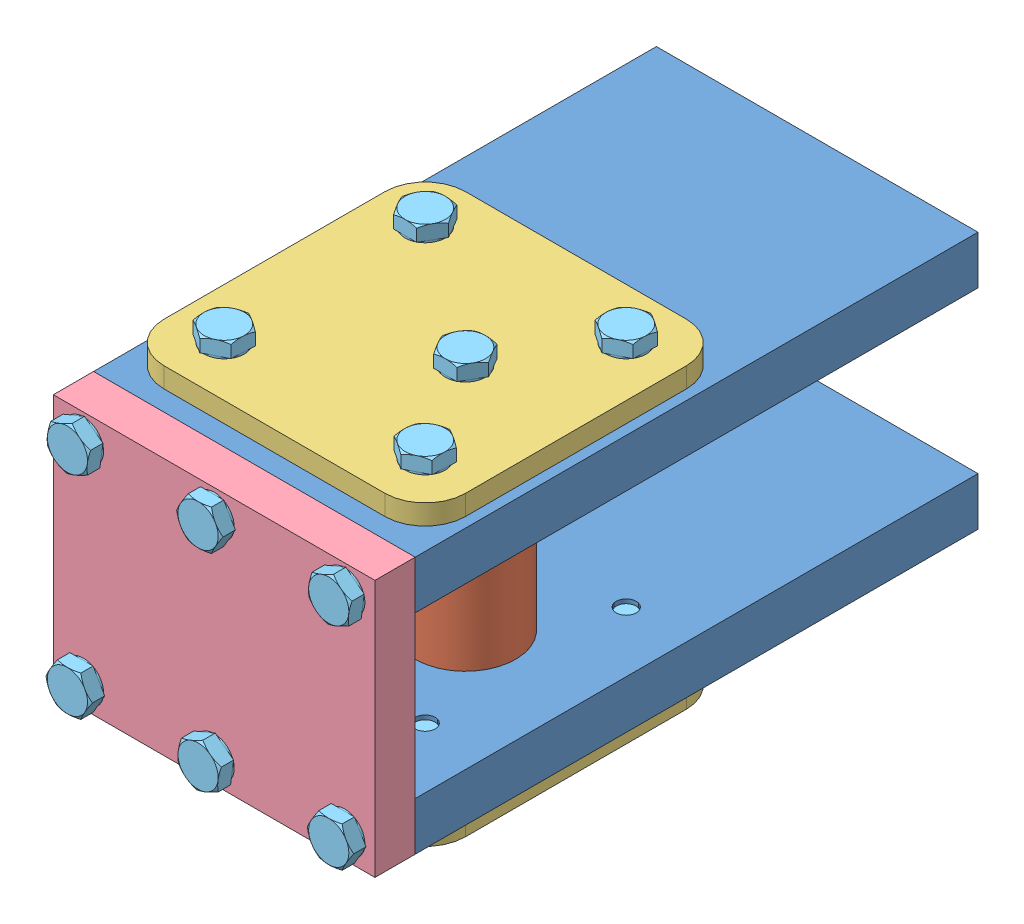
SolidWorks assembly 010300_cylinder_mount, configuration Default. Lengths in mm.
Overall size (80 82 154).
22 component instances, 5 part files, 49 mates.
Components (placement in the parent):
- 010301_cylinder_mount_front-1: 010301_cylinder_mount_front [Default] at (0 -26 0) size (80 12 140)
- 010301_cylinder_mount_front-2: 010301_cylinder_mount_front [Default] at (0 26 0) size (80 12 140)
- 010302_cylinder_mount_pin-1: 010302_cylinder_mount_pin [Default] at (10 0 -42.5) x (0.998607 0 0.052773) z (0 -1 0) size (25 25 64)
- 010303_cylinder_mount_pincover-1: 010303_cylinder_mount_pincover [Default] at (0 32 -42.5) x (1 0 0) z (0 1 0) size (75 75 5)
- 010303_cylinder_mount_pincover-2: 010303_cylinder_mount_pincover [Default] at (0 -32 -42.5) x (1 0 0) z (0 -1 0) size (75 75 5)
- 010304_cylinder_mount_bottom-1: 010304_cylinder_mount_bottom [Default] at (-40 0 0) size (80 64 10)
- hex screw gradeab_iso-1: hex screw gradeab_iso [ISO 4017 - M6 x 16-N] at (-25 41 -67.5) x (0 -1 0) z (0 0 -1) size (20 11.55 10)
- hex screw gradeab_iso-2: hex screw gradeab_iso [ISO 4017 - M6 x 16-N] at (25 41 -67.5) x (0 -1 0) z (-0.546944 0 0.837169) size (20 11.55 10)
- hex screw gradeab_iso-3: hex screw gradeab_iso [ISO 4017 - M6 x 16-N] at (10 41 -42.5) x (0 -1 0) z (0 0 -1) size (20 11.55 10)
- hex screw gradeab_iso-4: hex screw gradeab_iso [ISO 4017 - M6 x 16-N] at (-25 41 -17.5) x (0 -1 0) z (-0.546944 0 0.837169) size (20 11.55 10)
- hex screw gradeab_iso-5: hex screw gradeab_iso [ISO 4017 - M6 x 16-N] at (25 41 -17.5) x (0 -1 0) z (-0.546944 0 0.837169) size (20 11.55 10)
- hex screw gradeab_iso-6: hex screw gradeab_iso [ISO 4017 - M6 x 16-N] at (-25 -41 -67.5) x (0 1 0) z (-0.546944 0 -0.837169) size (20 11.55 10)
- hex screw gradeab_iso-7: hex screw gradeab_iso [ISO 4017 - M6 x 16-N] at (25 -41 -67.5) x (0 1 0) z (-0.546944 0 -0.837169) size (20 11.55 10)
- hex screw gradeab_iso-8: hex screw gradeab_iso [ISO 4017 - M6 x 16-N] at (10 -41 -42.5) x (0 1 0) z (-0.546944 0 -0.837169) size (20 11.55 10)
- hex screw gradeab_iso-9: hex screw gradeab_iso [ISO 4017 - M6 x 16-N] at (-25 -41 -17.5) x (0 1 0) z (0 0 1) size (20 11.55 10)
- hex screw gradeab_iso-10: hex screw gradeab_iso [ISO 4017 - M6 x 16-N] at (25 -41 -17.5) x (0 1 0) z (0 0 1) size (20 11.55 10)
- hex screw gradeab_iso-11: hex screw gradeab_iso [ISO 4017 - M6 x 16-N] at (-32.5 26 14) x (0 0 -1) z (0.383049 -0.923728 0) size (20 11.55 10)
- hex screw gradeab_iso-12: hex screw gradeab_iso [ISO 4017 - M6 x 16-N] at (0 26 14) x (0 0 -1) z (0 1 0) size (20 11.55 10)
- hex screw gradeab_iso-13: hex screw gradeab_iso [ISO 4017 - M6 x 16-N] at (0 -26 14) x (0 0 -1) z (0.383049 -0.923728 0) size (20 11.55 10)
- hex screw gradeab_iso-14: hex screw gradeab_iso [ISO 4017 - M6 x 16-N] at (32.5 -26 14) x (0 0 -1) z (0 1 0) size (20 11.55 10)
- hex screw gradeab_iso-15: hex screw gradeab_iso [ISO 4017 - M6 x 16-N] at (-32.5 -26 14) x (0 0 -1) z (0 1 0) size (20 11.55 10)
- hex screw gradeab_iso-16: hex screw gradeab_iso [ISO 4017 - M6 x 16-N] at (32.5 26 14) x (0 0 -1) z (0.383049 -0.923728 0) size (20 11.55 10)
Mates (geometry in assembly coordinates):
- Coincident1: coincident aligned: plane of 010301_cylinder_mount_front-1 through (0 -26 0) normal (0 0 1)
- Coincident3: coincident aligned: plane of 010301_cylinder_mount_front-1 through (0 -26 0) normal (1 0 0)
- Concentric1: concentric anti-aligned: cylinder of 010301_cylinder_mount_front-2 through (10 32 -42.5) axis (0 -1 0) radius 12.5; cylinder of 010302_cylinder_mount_pin-1 through (10 -32 -42.5) axis (0 1 0) radius 12.5
- Coincident13: coincident aligned: plane of 010301_cylinder_mount_front-2 through (0 32 0) normal (0 1 0); plane of 010302_cylinder_mount_pin-1 through (10 32 -42.5) normal (0 1 0)
- Concentric2: concentric anti-aligned: cylinder of 010301_cylinder_mount_front-1 through (10 -20 -42.5) axis (0 -1 0) radius 12.5; cylinder of 010302_cylinder_mount_pin-1 through (10 -32 -42.5) axis (0 1 0) radius 12.5
- Coincident17: coincident aligned: plane of 010301_cylinder_mount_front-1 through (0 -32 0) normal (0 -1 0); plane of 010302_cylinder_mount_pin-1 through (10 -32 -42.5) normal (0 -1 0)
- Coincident18: coincident anti-aligned: plane of 010302_cylinder_mount_pin-1 through (10 0 -42.5) normal (0 -1 0)
- Coincident20: coincident aligned: plane of 010301_cylinder_mount_front-1 through (-40 -20 -140) normal (-1 0 0); plane of 010301_cylinder_mount_front-2 through (-40 32 -140) normal (-1 0 0)
- Coincident23: coincident anti-aligned: plane of 010301_cylinder_mount_front-2 through (0 32 0) normal (0 1 0); plane of 010303_cylinder_mount_pincover-1 through (0 32 -42.5) normal (0 -1 0)
- Concentric5: concentric aligned: cylinder of 010301_cylinder_mount_front-2 through (25 32 -67.5) axis (0 1 0) radius 2.5; circle of Cylinderfixture_pincover-1
- Concentric6: concentric aligned: cylinder of 010301_cylinder_mount_front-2 through (25 32 -17.5) axis (0 1 0) radius 2.5; cylinder of 010303_cylinder_mount_pincover-1 through (25 37 -17.5) axis (0 1 0) radius 3.5
- Coincident24: coincident anti-aligned: plane of 010301_cylinder_mount_front-1 through (0 -32 0) normal (0 -1 0); plane of 010303_cylinder_mount_pincover-2 through (0 -32 -42.5) normal (0 1 0)
- Concentric7: concentric anti-aligned: cylinder of 010301_cylinder_mount_front-1 through (25 -20 -67.5) axis (0 1 0) radius 2.5; cylinder of 010303_cylinder_mount_pincover-2 through (25 -37 -67.5) axis (0 -1 0) radius 3.5
- Concentric8: concentric anti-aligned: cylinder of 010301_cylinder_mount_front-1 through (25 -20 -17.5) axis (0 1 0) radius 2.5; cylinder of 010303_cylinder_mount_pincover-2 through (25 -37 -17.5) axis (0 -1 0) radius 3.5
- Concentric9: concentric aligned: cylinder of 010303_cylinder_mount_pincover-1 through (-25 37 -67.5) axis (0 1 0) radius 3.5; cylinder of hex screw gradeab_iso-1 through (-25 41 -67.5) axis (0 1 0) radius 3
- Concentric10: concentric aligned: cylinder of 010303_cylinder_mount_pincover-1 through (25 37 -67.5) axis (0 1 0) radius 3.5; cylinder of hex screw gradeab_iso-2 through (25 41 -67.5) axis (0 1 0) radius 3
- Concentric11: concentric aligned: cylinder of 010303_cylinder_mount_pincover-1 through (10 37 -42.5) axis (0 1 0) radius 3.5; cylinder of hex screw gradeab_iso-3 through (10 41 -42.5) axis (0 1 0) radius 3
- Concentric12: concentric aligned: cylinder of 010303_cylinder_mount_pincover-1 through (-25 37 -17.5) axis (0 1 0) radius 3.5; cylinder of hex screw gradeab_iso-4 through (-25 41 -17.5) axis (0 1 0) radius 3
- Concentric13: concentric aligned: cylinder of 010303_cylinder_mount_pincover-1 through (25 37 -17.5) axis (0 1 0) radius 3.5; cylinder of hex screw gradeab_iso-5 through (25 41 -17.5) axis (0 1 0) radius 3
- Coincident25: coincident anti-aligned: plane of 010303_cylinder_mount_pincover-1 through (0 37 -42.5) normal (0 1 0); plane of hex screw gradeab_iso-3 through (4.2265 37 -42.5) normal (0 -1 0)
- Coincident26: coincident anti-aligned: plane of 010303_cylinder_mount_pincover-1 through (0 37 -42.5) normal (0 1 0); plane of hex screw gradeab_iso-1 through (-30.7735 37 -67.5) normal (0 -1 0)
- Coincident27: coincident anti-aligned: plane of 010303_cylinder_mount_pincover-1 through (0 37 -42.5) normal (0 1 0); plane of hex screw gradeab_iso-2 through (29.8334 37 -64.3422) normal (0 -1 0)
- Coincident28: coincident anti-aligned: plane of 010303_cylinder_mount_pincover-1 through (0 37 -42.5) normal (0 1 0); plane of hex screw gradeab_iso-4 through (-20.1666 37 -14.3422) normal (0 -1 0)
- Coincident29: coincident anti-aligned: plane of 010303_cylinder_mount_pincover-1 through (0 37 -42.5) normal (0 1 0); plane of hex screw gradeab_iso-5 through (29.8334 37 -14.3422) normal (0 -1 0)
- Concentric14: concentric aligned: cylinder of 010303_cylinder_mount_pincover-2 through (25 -37 -67.5) axis (0 -1 0) radius 3.5; cylinder of hex screw gradeab_iso-7 through (25 -41 -67.5) axis (0 -1 0) radius 3
- Concentric15: concentric aligned: cylinder of 010303_cylinder_mount_pincover-2 through (-25 -37 -67.5) axis (0 -1 0) radius 3.5; cylinder of hex screw gradeab_iso-6 through (-25 -41 -67.5) axis (0 -1 0) radius 3
- Concentric16: concentric aligned: cylinder of 010303_cylinder_mount_pincover-2 through (10 -37 -42.5) axis (0 -1 0) radius 3.5; cylinder of hex screw gradeab_iso-8 through (10 -41 -42.5) axis (0 -1 0) radius 3
- Concentric17: concentric aligned: cylinder of 010303_cylinder_mount_pincover-2 through (-25 -37 -17.5) axis (0 -1 0) radius 3.5; cylinder of hex screw gradeab_iso-9 through (-25 -41 -17.5) axis (0 -1 0) radius 3
- Concentric18: concentric aligned: cylinder of 010303_cylinder_mount_pincover-2 through (25 -37 -17.5) axis (0 -1 0) radius 3.5; cylinder of hex screw gradeab_iso-10 through (25 -41 -17.5) axis (0 -1 0) radius 3
- Coincident31: coincident anti-aligned: plane of 010303_cylinder_mount_pincover-2 through (0 -37 -42.5) normal (0 -1 0); plane of hex screw gradeab_iso-6 through (-20.1666 -37 -70.6578) normal (0 1 0)
- Coincident32: coincident anti-aligned: plane of 010303_cylinder_mount_pincover-2 through (0 -37 -42.5) normal (0 -1 0); plane of hex screw gradeab_iso-7 through (29.8334 -37 -70.6578) normal (0 1 0)
- Coincident33: coincident anti-aligned: plane of 010303_cylinder_mount_pincover-2 through (0 -37 -42.5) normal (0 -1 0); plane of hex screw gradeab_iso-8 through (14.8334 -37 -45.6578) normal (0 1 0)
- Coincident34: coincident anti-aligned: plane of 010303_cylinder_mount_pincover-2 through (0 -37 -42.5) normal (0 -1 0); plane of hex screw gradeab_iso-9 through (-30.7735 -37 -17.5) normal (0 1 0)
- Coincident35: coincident anti-aligned: plane of 010303_cylinder_mount_pincover-2 through (0 -37 -42.5) normal (0 -1 0); plane of hex screw gradeab_iso-10 through (19.2265 -37 -17.5) normal (0 1 0)
- Coincident36: coincident anti-aligned: plane of 010301_cylinder_mount_front-2 through (-40 32 0) normal (0 0 1); plane of 010304_cylinder_mount_bottom-1 through (-40 0 0) normal (0 0 -1)
- Coincident37: coincident aligned: plane of 010301_cylinder_mount_front-2 through (0 32 0) normal (0 1 0); plane of 010304_cylinder_mount_bottom-1 through (-40 32 10) normal (0 1 0)
- Coincident38: coincident aligned: plane of 010301_cylinder_mount_front-2 through (40 32 -140) normal (1 0 0); plane of 010304_cylinder_mount_bottom-1 through (40 32 10) normal (1 0 0)
- Concentric19: concentric aligned: cylinder of 010304_cylinder_mount_bottom-1 through (-32.5 26 10) axis (0 0 1) radius 3.5; cylinder of hex screw gradeab_iso-11 through (-32.5 26 14) axis (0 0 1) radius 3
- Concentric20: concentric aligned: cylinder of 010304_cylinder_mount_bottom-1 through (0 26 10) axis (0 0 1) radius 3.5; cylinder of hex screw gradeab_iso-12 through (0 26 14) axis (0 0 1) radius 3
- Concentric21: concentric aligned: cylinder of 010304_cylinder_mount_bottom-1 through (32.5 26 10) axis (0 0 1) radius 3.5; cylinder of hex screw gradeab_iso-16 through (32.5 26 14) axis (0 0 1) radius 3
- Concentric22: concentric aligned: cylinder of 010304_cylinder_mount_bottom-1 through (-32.5 -26 10) axis (0 0 1) radius 3.5; cylinder of hex screw gradeab_iso-15 through (-32.5 -26 14) axis (0 0 1) radius 3
- Concentric23: concentric aligned: cylinder of 010304_cylinder_mount_bottom-1 through (0 -26 10) axis (0 0 1) radius 3.5; cylinder of hex screw gradeab_iso-13 through (0 -26 14) axis (0 0 1) radius 3
- Concentric24: concentric aligned: cylinder of 010304_cylinder_mount_bottom-1 through (32.5 -26 10) axis (0 0 1) radius 3.5; cylinder of hex screw gradeab_iso-14 through (32.5 -26 14) axis (0 0 1) radius 3
- Coincident39: coincident anti-aligned: plane of 010304_cylinder_mount_bottom-1 through (-40 0 10) normal (0 0 1); plane of hex screw gradeab_iso-15 through (-38.2735 -26 10) normal (0 0 -1)
- Coincident40: coincident anti-aligned: plane of 010304_cylinder_mount_bottom-1 through (-40 0 10) normal (0 0 1); plane of hex screw gradeab_iso-13 through (5.3331 -23.7885 10) normal (0 0 -1)
- Coincident41: coincident anti-aligned: plane of 010304_cylinder_mount_bottom-1 through (-40 0 10) normal (0 0 1); plane of hex screw gradeab_iso-14 through (26.7265 -26 10) normal (0 0 -1)
- Coincident42: coincident anti-aligned: plane of 010304_cylinder_mount_bottom-1 through (-40 0 10) normal (0 0 1); plane of hex screw gradeab_iso-11 through (-27.1669 28.2115 10) normal (0 0 -1)
- Coincident43: coincident anti-aligned: plane of 010304_cylinder_mount_bottom-1 through (-40 0 10) normal (0 0 1); plane of hex screw gradeab_iso-12 through (-5.7735 26 10) normal (0 0 -1)
- Coincident44: coincident anti-aligned: plane of 010304_cylinder_mount_bottom-1 through (-40 0 10) normal (0 0 1); plane of hex screw gradeab_iso-16 through (37.8331 28.2115 10) normal (0 0 -1)
